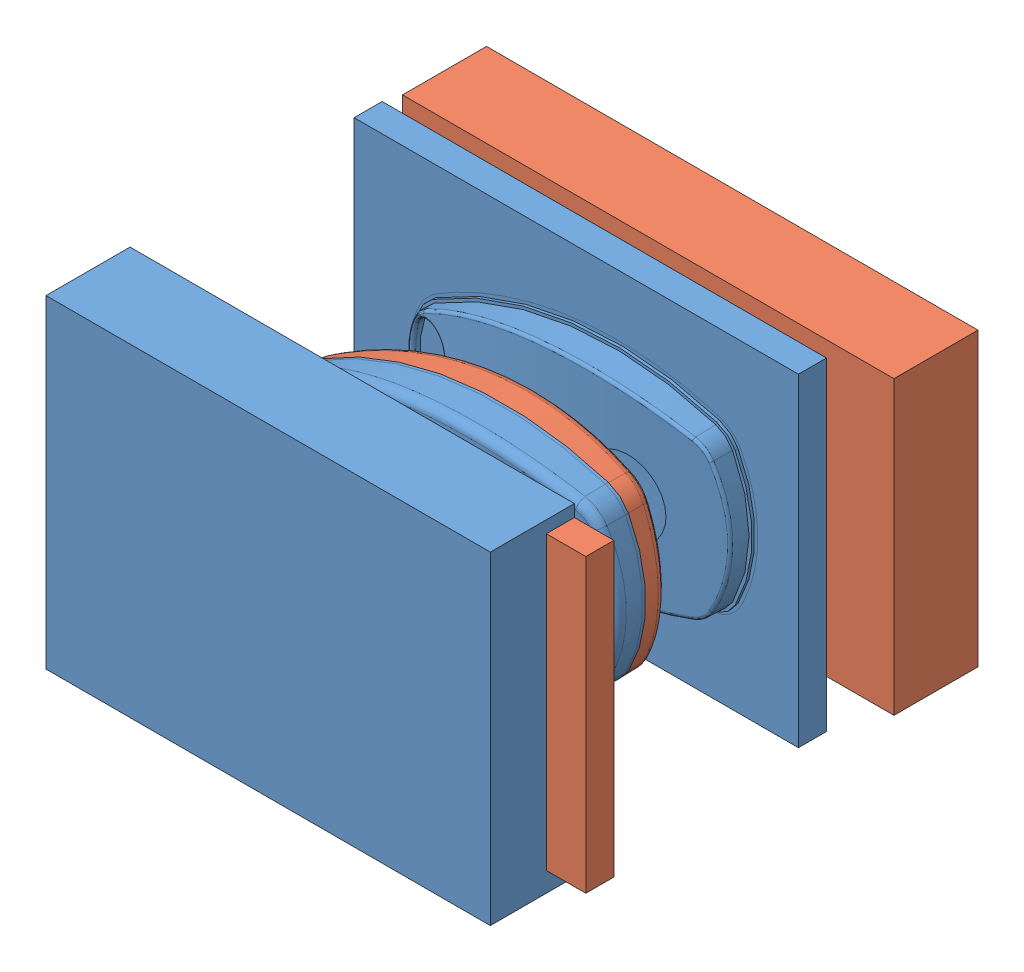
SolidWorks assembly Sestava1, configuration Default. Lengths in mm.
Overall size (87.73 66.49 80).
4 component instances, 4 part files, 9 mates.
Components (placement in the parent):
- Díl3_1-1: Díl3_1 [Default] at origin size (79.31 57.74 60)
- Díl3_2-1: Díl3_2 [Default] at (0.0238 0 -0.2306) x (1 0 0) z (0 0 -1) size (87.73 64.33 70)
- Ovladac_deska-1: Ovladac_deska [Default] at (-25 0 -0.1146) x (-1 0 0) z (0 1 0) size (35 1 25)
- Ovladac_tlacitko-1: Ovladac_tlacitko [Default] at (-17.54 0 0.7554) x (0 0 1) z (1 0 0) size (5.25 13 13)
Mates (geometry in assembly coordinates):
- Sjednocená1: coordinate: point of Díl3_1-1; point of assembly
- Sjednocená18: coincident: plane of Díl3_1-1 through (0.8432 0 -0.6296) normal (0 0 -1); plane of Díl3_2-1 through (-16.0259 17.248 -0.6296) normal (0 0 1)
- Soustředná8: concentric: circle of Díl3_2-1; circle of Díl3_1-1
- Sjednocená24: coincident: plane of Díl3_2-1 through (-40.3568 -10.3 -0.1146) normal (0 0 1); plane of Ovladac_deska-1 through (-25 0 -0.1146) normal (0 0 -1)
- Soustředná14: concentric: circle of Díl3_2-1; circle of Ovladac_deska-1
- Soustředná15: concentric: circle of Díl3_2-1; circle of Ovladac_deska-1
- Soustředná16: concentric: circle of Díl3_1-1; circle of Díl3_2-1
- Sjednocená25: coincident: plane of Díl3_1-1 through (-23.918 0.0057 4.0054) normal (0 0 -1); plane of Ovladac_tlacitko-1 through (-17.54 -6.5 4.0054) normal (0 0 1)
- Soustředná17: concentric: circle of Díl3_1-1; circle of Ovladac_tlacitko-1
